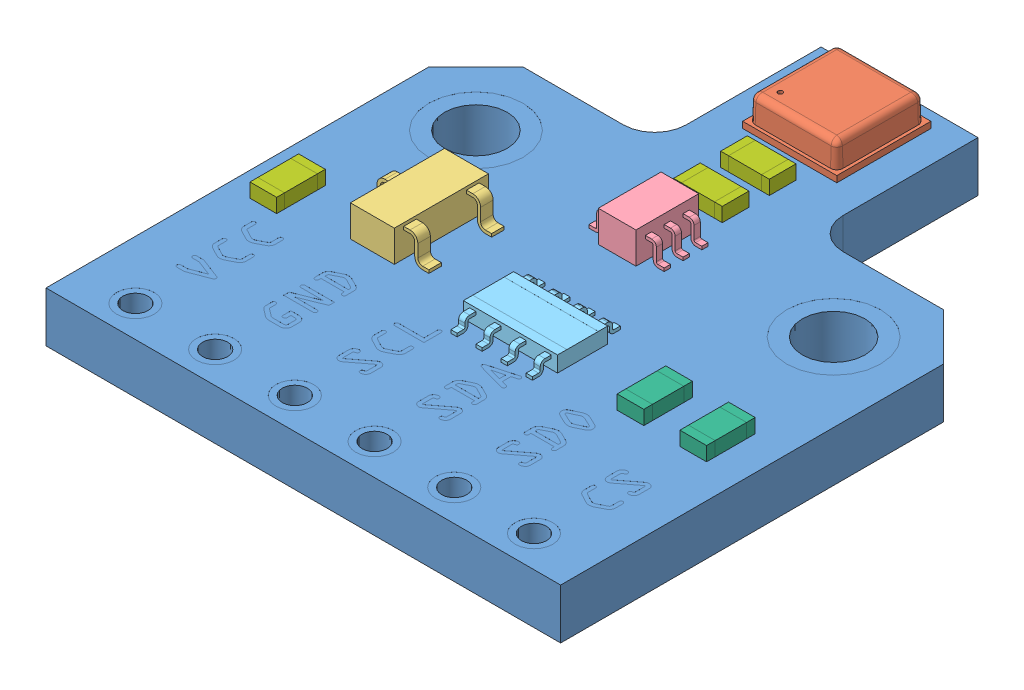
SolidWorks assembly CJMCU-680, BME680 Ambient Temperature, Relative Humidity, Barometric Pressure, and Gas VOC Sensor, configuration Default. Lengths in mm.
Overall size (16.4 2.6 19).
10 component instances, 7 part files, 28 mates.
Components (placement in the parent):
- PCB, CJMCU-680, BME680 Ambient Temperature, Relative Humidity, Barometric Pressure, and Gas VOC Sensor-1: PCB, CJMCU-680, BME680 Ambient Temperature, Relative Humidity, Barometric Pressure, and Gas VOC Sensor [Default] at origin size (16.4 1.6 19)
- Sensor Module, CJMCU-680, BME680 Ambient Temperature, Relative Humidity, Barometric Pressure, and Gas VOC Sensor-1: Sensor Module, CJMCU-680, BME680 Ambient Temperature, Relative Humidity, Barometric Pressure, and Gas VOC Sensor [Default] at (0 0.8 -10.15) size (3 1.01 3)
- 3.3V LDO Regulator, CJMCU-680, BME680 Ambient Temperature, Relative Humidity, Barometric Pressure, and Gas VOC Sensor-1: 3.3V LDO Regulator, CJMCU-680, BME680 Ambient Temperature, Relative Humidity, Barometric Pressure, and Gas VOC Sensor [Default] at (-4 1.3 -0.85) size (3 1 3)
- Level Signal Conversion Chip, CJMCU-680, BME680 Ambient Temperature, Relative Humidity, Barometric Pressure, and Gas VOC Sensor-1: Level Signal Conversion Chip, CJMCU-680, BME680 Ambient Temperature, Relative Humidity, Barometric Pressure, and Gas VOC Sensor [Default] at (0 1.3 -4.15) size (2.4 1 2)
- 8 Legs SMD Component, CJMCU-680, BME680 Ambient Temperature, Relative Humidity, Barometric Pressure, and Gas VOC Sensor-1: 8 Legs SMD Component, CJMCU-680, BME680 Ambient Temperature, Relative Humidity, Barometric Pressure, and Gas VOC Sensor [Default] at (0.8 1.05 0.25) x (0 0 -1) z (1 0 0) size (2.8 0.5 3)
- SMD Resistor, Configurable, CJMCU-680, BME680 Ambient Temperature, Relative Humidity, Barometric Pressure, and Gas VOC Sensor-1: SMD Resistor, Configurable, CJMCU-680, BME680 Ambient Temperature, Relative Humidity, Barometric Pressure, and Gas VOC Sensor [R2] at (4.7 0.8 0.35) size (0.85 0.45 1.55)
- SMD Resistor, Configurable, CJMCU-680, BME680 Ambient Temperature, Relative Humidity, Barometric Pressure, and Gas VOC Sensor-2: SMD Resistor, Configurable, CJMCU-680, BME680 Ambient Temperature, Relative Humidity, Barometric Pressure, and Gas VOC Sensor [R1] at (6.7 0.8 0.35) size (0.85 0.45 1.55)
- SMD Capacitor, Configurable, CJMCU-680, BME680 Ambient Temperature, Relative Humidity, Barometric Pressure, and Gas VOC Sensor-1: SMD Capacitor, Configurable, CJMCU-680, BME680 Ambient Temperature, Relative Humidity, Barometric Pressure, and Gas VOC Sensor [C1] at (-7 0.8 0.35) size (0.85 0.45 1.55)
- SMD Capacitor, Configurable, CJMCU-680, BME680 Ambient Temperature, Relative Humidity, Barometric Pressure, and Gas VOC Sensor-2: SMD Capacitor, Configurable, CJMCU-680, BME680 Ambient Temperature, Relative Humidity, Barometric Pressure, and Gas VOC Sensor [C2] at (0 0.8 -6.15) x (0 0 1) z (-1 0 0) size (0.85 0.45 1.55)
- SMD Capacitor, Configurable, CJMCU-680, BME680 Ambient Temperature, Relative Humidity, Barometric Pressure, and Gas VOC Sensor-3: SMD Capacitor, Configurable, CJMCU-680, BME680 Ambient Temperature, Relative Humidity, Barometric Pressure, and Gas VOC Sensor [C3] at (0 0.8 -7.65) x (0 0 1) z (-1 0 0) size (0.85 0.45 1.55)
Mates (geometry in assembly coordinates):
- Coincident1: coincident: plane of assembly through (0 0 0) normal (1 0 0); plane of Sensor Module, CJMCU-680, BME680 Ambient Temperature, Relative Humidity, Barometric Pressure, and Gas VOC Sensor-1 through (0 0.8 -10.15) normal (1 0 0); plane of assembly
- Coincident2: coincident: plane of assembly; plane of assembly; plane of PCB, CJMCU-680, BME680 Ambient Temperature, Relative Humidity, Barometric Pressure, and Gas VOC Sensor-1 through (0 0.8 0) normal (0 1 0); plane of Sensor Module, CJMCU-680, BME680 Ambient Temperature, Relative Humidity, Barometric Pressure, and Gas VOC Sensor-1 through (0 0.8 -10.15) normal (0 -1 0)
- Distance1: distance = 0.5 mm: plane of assembly; plane of assembly; plane of PCB, CJMCU-680, BME680 Ambient Temperature, Relative Humidity, Barometric Pressure, and Gas VOC Sensor-1 through (-2.5 0.8 -12.15) normal (0 0 -1); plane of Sensor Module, CJMCU-680, BME680 Ambient Temperature, Relative Humidity, Barometric Pressure, and Gas VOC Sensor-1 through (-1.5 1 -11.65) normal (0 0 -1)
- Coincident3: coordinate: point of assembly; point of PCB, CJMCU-680, BME680 Ambient Temperature, Relative Humidity, Barometric Pressure, and Gas VOC Sensor-1; point of assembly
- Coincident4: coincident: plane of assembly; plane of assembly; plane of PCB, CJMCU-680, BME680 Ambient Temperature, Relative Humidity, Barometric Pressure, and Gas VOC Sensor-1 through (0 0.8 0) normal (0 1 0); plane of 3.3V LDO Regulator, CJMCU-680, BME680 Ambient Temperature, Relative Humidity, Barometric Pressure, and Gas VOC Sensor-1 through (-4 0.8 -0.85) normal (0 -1 0)
- Coincident5: coincident: plane of assembly; plane of assembly; plane of PCB, CJMCU-680, BME680 Ambient Temperature, Relative Humidity, Barometric Pressure, and Gas VOC Sensor-1 through (0 0.8 0) normal (0 1 0); plane of SMD Resistor, Configurable, CJMCU-680, BME680 Ambient Temperature, Relative Humidity, Barometric Pressure, and Gas VOC Sensor-1 through (4.7 0.8 0.35) normal (0 -1 0)
- Coincident6: coincident: plane of assembly; plane of assembly; plane of PCB, CJMCU-680, BME680 Ambient Temperature, Relative Humidity, Barometric Pressure, and Gas VOC Sensor-1 through (0 0.8 0) normal (0 1 0); plane of SMD Capacitor, Configurable, CJMCU-680, BME680 Ambient Temperature, Relative Humidity, Barometric Pressure, and Gas VOC Sensor-1 through (-7 0.8 0.35) normal (0 -1 0)
- Coincident7: coincident: plane of assembly; plane of assembly; plane of PCB, CJMCU-680, BME680 Ambient Temperature, Relative Humidity, Barometric Pressure, and Gas VOC Sensor-1 through (0 0.8 0) normal (0 1 0); plane of SMD Resistor, Configurable, CJMCU-680, BME680 Ambient Temperature, Relative Humidity, Barometric Pressure, and Gas VOC Sensor-2 through (6.7 0.8 0.35) normal (0 -1 0)
- Coincident8: coincident: plane of assembly; plane of assembly; plane of SMD Resistor, Configurable, CJMCU-680, BME680 Ambient Temperature, Relative Humidity, Barometric Pressure, and Gas VOC Sensor-1 through (4.7 0.8 0.35) normal (0 0 1); plane of SMD Resistor, Configurable, CJMCU-680, BME680 Ambient Temperature, Relative Humidity, Barometric Pressure, and Gas VOC Sensor-2 through (6.7 0.8 0.35) normal (0 0 1)
- Coincident9: coincident: plane of assembly; plane of assembly; plane of SMD Capacitor, Configurable, CJMCU-680, BME680 Ambient Temperature, Relative Humidity, Barometric Pressure, and Gas VOC Sensor-2 through (0 0.8 -6.15) normal (-1 0 0); plane of SMD Capacitor, Configurable, CJMCU-680, BME680 Ambient Temperature, Relative Humidity, Barometric Pressure, and Gas VOC Sensor-3 through (0 0.8 -7.65) normal (-1 0 0)
- Coincident10: coincident: plane of assembly through (0 0 0) normal (1 0 0); plane of SMD Capacitor, Configurable, CJMCU-680, BME680 Ambient Temperature, Relative Humidity, Barometric Pressure, and Gas VOC Sensor-3 through (0 0.8 -7.65) normal (-1 0 0); plane of assembly
- Coincident11: coincident: plane of assembly; plane of assembly; plane of SMD Capacitor, Configurable, CJMCU-680, BME680 Ambient Temperature, Relative Humidity, Barometric Pressure, and Gas VOC Sensor-2 through (0 0.8 -6.15) normal (0 -1 0); plane of SMD Capacitor, Configurable, CJMCU-680, BME680 Ambient Temperature, Relative Humidity, Barometric Pressure, and Gas VOC Sensor-3 through (0 0.8 -7.65) normal (0 -1 0)
- Coincident12: coincident: plane of assembly; plane of assembly; plane of PCB, CJMCU-680, BME680 Ambient Temperature, Relative Humidity, Barometric Pressure, and Gas VOC Sensor-1 through (0 0.8 0) normal (0 1 0); plane of SMD Capacitor, Configurable, CJMCU-680, BME680 Ambient Temperature, Relative Humidity, Barometric Pressure, and Gas VOC Sensor-3 through (0 0.8 -7.65) normal (0 -1 0)
- Distance2: distance = 6.5 mm: plane of assembly; plane of assembly; plane of SMD Capacitor, Configurable, CJMCU-680, BME680 Ambient Temperature, Relative Humidity, Barometric Pressure, and Gas VOC Sensor-1 through (-7 0.8 0.35) normal (0 0 1); plane of PCB, CJMCU-680, BME680 Ambient Temperature, Relative Humidity, Barometric Pressure, and Gas VOC Sensor-1 through (-8.2 0.8 6.85) normal (0 0 1)
- Distance3: distance = 1.2 mm: plane of assembly; plane of assembly; plane of SMD Capacitor, Configurable, CJMCU-680, BME680 Ambient Temperature, Relative Humidity, Barometric Pressure, and Gas VOC Sensor-1 through (-7 0.8 0.35) normal (1 0 0); plane of PCB, CJMCU-680, BME680 Ambient Temperature, Relative Humidity, Barometric Pressure, and Gas VOC Sensor-1 through (-8.2 0.8 -6.85) normal (-1 0 0)
- Distance4: distance = 2 mm: plane of assembly; plane of assembly; plane of SMD Resistor, Configurable, CJMCU-680, BME680 Ambient Temperature, Relative Humidity, Barometric Pressure, and Gas VOC Sensor-1 through (4.7 0.8 0.35) normal (1 0 0); plane of SMD Resistor, Configurable, CJMCU-680, BME680 Ambient Temperature, Relative Humidity, Barometric Pressure, and Gas VOC Sensor-2 through (6.7 0.8 0.35) normal (1 0 0)
- Distance5: distance = 1.5 mm: plane of assembly; plane of assembly; plane of SMD Resistor, Configurable, CJMCU-680, BME680 Ambient Temperature, Relative Humidity, Barometric Pressure, and Gas VOC Sensor-2 through (6.7 0.8 0.35) normal (1 0 0); plane of PCB, CJMCU-680, BME680 Ambient Temperature, Relative Humidity, Barometric Pressure, and Gas VOC Sensor-1 through (8.2 0.8 -6.85) normal (1 0 0)
- Distance6: distance = 6.5 mm: plane of assembly; plane of assembly; plane of SMD Resistor, Configurable, CJMCU-680, BME680 Ambient Temperature, Relative Humidity, Barometric Pressure, and Gas VOC Sensor-2 through (6.7 0.8 0.35) normal (0 0 1); plane of PCB, CJMCU-680, BME680 Ambient Temperature, Relative Humidity, Barometric Pressure, and Gas VOC Sensor-1 through (-8.2 0.8 6.85) normal (0 0 1)
- Distance7: distance = 1.5 mm: plane of assembly; plane of assembly; plane of SMD Capacitor, Configurable, CJMCU-680, BME680 Ambient Temperature, Relative Humidity, Barometric Pressure, and Gas VOC Sensor-3 through (0 0.8 -7.65) normal (0 0 1); plane of SMD Capacitor, Configurable, CJMCU-680, BME680 Ambient Temperature, Relative Humidity, Barometric Pressure, and Gas VOC Sensor-2 through (0 0.8 -6.15) normal (0 0 1)
- Distance8: distance = 4.5 mm: plane of assembly; plane of assembly; plane of SMD Capacitor, Configurable, CJMCU-680, BME680 Ambient Temperature, Relative Humidity, Barometric Pressure, and Gas VOC Sensor-3 through (0 0.8 -7.65) normal (0 0 1); plane of PCB, CJMCU-680, BME680 Ambient Temperature, Relative Humidity, Barometric Pressure, and Gas VOC Sensor-1 through (-2.5 0.8 -12.15) normal (0 0 -1)
- Coincident13: coincident: plane of assembly; plane of assembly; plane of PCB, CJMCU-680, BME680 Ambient Temperature, Relative Humidity, Barometric Pressure, and Gas VOC Sensor-1 through (0 0.8 0) normal (0 1 0); plane of Level Signal Conversion Chip, CJMCU-680, BME680 Ambient Temperature, Relative Humidity, Barometric Pressure, and Gas VOC Sensor-1 through (0 0.8 -4.15) normal (0 -1 0)
- Coincident14: coincident: plane of assembly through (0 0 0) normal (1 0 0); plane of Level Signal Conversion Chip, CJMCU-680, BME680 Ambient Temperature, Relative Humidity, Barometric Pressure, and Gas VOC Sensor-1 through (0 1.3 -4.15) normal (1 0 0); plane of assembly
- Distance9: distance = 8 mm: plane of assembly; plane of assembly; plane of Level Signal Conversion Chip, CJMCU-680, BME680 Ambient Temperature, Relative Humidity, Barometric Pressure, and Gas VOC Sensor-1 through (0 1.3 -4.15) normal (0 0 1); plane of PCB, CJMCU-680, BME680 Ambient Temperature, Relative Humidity, Barometric Pressure, and Gas VOC Sensor-1 through (-2.5 0.8 -12.15) normal (0 0 -1)
- Distance10: distance = 6 mm: plane of assembly; plane of assembly; plane of 3.3V LDO Regulator, CJMCU-680, BME680 Ambient Temperature, Relative Humidity, Barometric Pressure, and Gas VOC Sensor-1 through (-4 1.3 -0.85) normal (0 0 1); plane of PCB, CJMCU-680, BME680 Ambient Temperature, Relative Humidity, Barometric Pressure, and Gas VOC Sensor-1 through (-8.2 0.8 -6.85) normal (0 0 -1)
- Distance11: distance = 4.2 mm: plane of assembly; plane of assembly; plane of 3.3V LDO Regulator, CJMCU-680, BME680 Ambient Temperature, Relative Humidity, Barometric Pressure, and Gas VOC Sensor-1 through (-4 1.3 -0.85) normal (1 0 0); plane of PCB, CJMCU-680, BME680 Ambient Temperature, Relative Humidity, Barometric Pressure, and Gas VOC Sensor-1 through (-8.2 0.8 -6.85) normal (-1 0 0)
- Coincident15: coincident: plane of assembly; plane of assembly; plane of PCB, CJMCU-680, BME680 Ambient Temperature, Relative Humidity, Barometric Pressure, and Gas VOC Sensor-1 through (0 0.8 0) normal (0 1 0); plane of 8 Legs SMD Component, CJMCU-680, BME680 Ambient Temperature, Relative Humidity, Barometric Pressure, and Gas VOC Sensor-1 through (0.8 0.8 0.25) normal (0 -1 0)
- Distance12: distance = 7.4 mm: plane of assembly; plane of assembly; plane of 8 Legs SMD Component, CJMCU-680, BME680 Ambient Temperature, Relative Humidity, Barometric Pressure, and Gas VOC Sensor-1 through (0.8 1.05 0.25) normal (1 0 0); plane of PCB, CJMCU-680, BME680 Ambient Temperature, Relative Humidity, Barometric Pressure, and Gas VOC Sensor-1 through (8.2 0.8 -6.85) normal (1 0 0)
- Distance13: distance = 6.6 mm: plane of assembly; plane of assembly; plane of 8 Legs SMD Component, CJMCU-680, BME680 Ambient Temperature, Relative Humidity, Barometric Pressure, and Gas VOC Sensor-1 through (0.8 1.05 0.25) normal (0 0 -1); plane of PCB, CJMCU-680, BME680 Ambient Temperature, Relative Humidity, Barometric Pressure, and Gas VOC Sensor-1 through (-8.2 0.8 6.85) normal (0 0 1)
